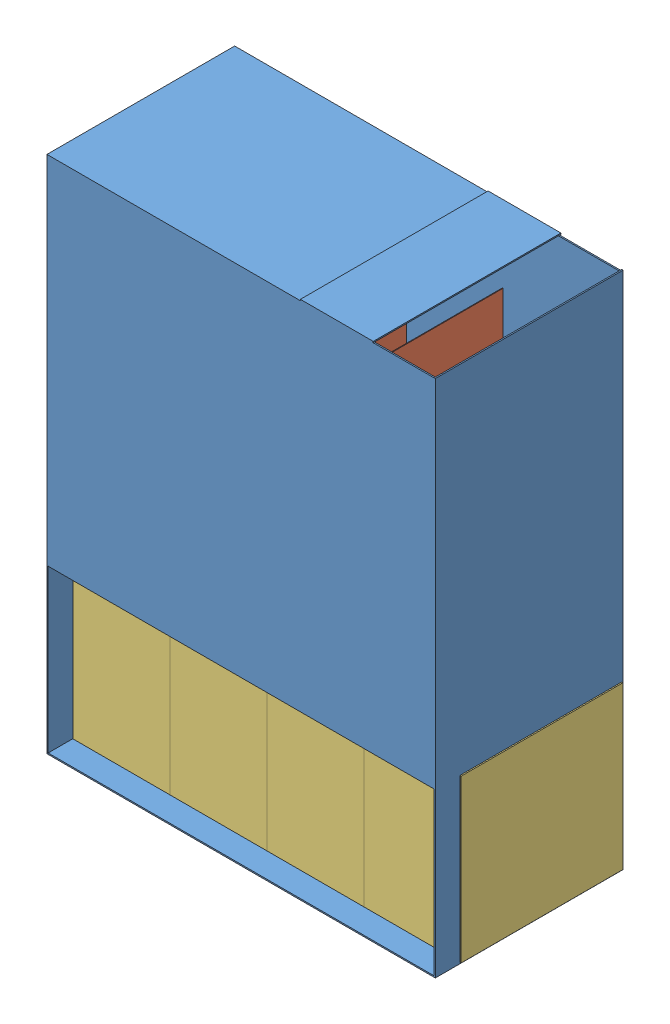
SolidWorks assembly Main body, configuration 默认. Lengths in mm.
Overall size (601.88 803.75 290).
6 component instances, 3 part files, 14 mates.
Components (placement in the parent):
- Shell-1: Shell [默认] at (-498.4129 -376.4154 658.7509) size (600 803.75 290)
- Sorting lane-1: Sorting lane [默认] at (-61.6372 160.9155 679.7509) size (476.17 356.5 269)
- Box-1: Box [默认] at (-346.5374 -374.4154 660.7509) x (0 0 1) z (-1 0 0) size (250 250 150)
- Box-2: Box [默认] at (-346.5374 -374.4154 910.7509) x (0 0 -1) z (1 0 0) size (250 250 150)
- Box-3: Box [默认] at (103.4626 -374.4154 660.7509) x (0 0 1) z (-1 0 0) size (250 250 150)
- Box-4: Box [默认] at (-46.5374 -374.4154 660.7509) x (0 0 1) z (-1 0 0) size (250 250 150)
Mates (geometry in assembly coordinates):
- 重合5: coincident anti-aligned: plane of Shell-1 through (-496.5374 -374.4154 948.7509) normal (0 1 0); plane of Box-1 through (-496.5374 -374.4154 660.7509) normal (0 -1 0)
- 重合6: coincident anti-aligned: plane of Shell-1 through (-496.5374 -374.4154 948.7509) normal (1 0 0); plane of Box-1 through (-496.5374 -374.4154 660.7509) normal (-1 0 0)
- 重合7: coincident anti-aligned: plane of Shell-1 through (-498.4129 423.5846 660.7509) normal (0 0 1); plane of Box-1 through (-496.5374 -374.4154 660.7509) normal (0 0 -1)
- 重合8: coincident anti-aligned: plane of Shell-1 through (-498.4129 423.5846 660.7509) normal (0 0 1); plane of Box-2 through (-196.5374 -374.4154 660.7509) normal (0 0 -1)
- 重合9: coincident anti-aligned: plane of Box-1 through (-346.5374 -374.4154 660.7509) normal (1 0 0); plane of Box-2 through (-346.5374 -374.4154 910.7509) normal (-1 0 0)
- 重合10: coincident anti-aligned: plane of Shell-1 through (-496.5374 -374.4154 948.7509) normal (0 1 0); plane of Box-2 through (-196.5374 -374.4154 910.7509) normal (0 -1 0)
- 重合11: coincident anti-aligned: plane of Box-2 through (-196.5374 -374.4154 910.7509) normal (1 0 0); plane of Box-4 through (-196.5374 -374.4154 660.7509) normal (-1 0 0)
- 重合12: coincident anti-aligned: plane of Shell-1 through (-498.4129 423.5846 660.7509) normal (0 0 1); plane of Box-4 through (-196.5374 -374.4154 660.7509) normal (0 0 -1)
- 重合13: coincident anti-aligned: plane of Shell-1 through (-496.5374 -374.4154 948.7509) normal (0 1 0); plane of Box-4 through (-196.5374 -374.4154 660.7509) normal (0 -1 0)
- 重合14: coincident anti-aligned: plane of Box-3 through (-46.5374 -374.4154 660.7509) normal (-1 0 0); plane of Box-4 through (-46.5374 -374.4154 660.7509) normal (1 0 0)
- 重合15: coincident anti-aligned: plane of Shell-1 through (-498.4129 423.5846 660.7509) normal (0 0 1); plane of Box-3 through (-46.5374 -374.4154 660.7509) normal (0 0 -1)
- 重合17: coincident anti-aligned: plane of Shell-1 through (-496.5374 -374.4154 948.7509) normal (0 1 0); plane of Box-3 through (-46.5374 -374.4154 660.7509) normal (0 -1 0)
- 相切1: tangent: plane of Shell-1 through (99.5871 -374.4154 948.7509) normal (-1 0 0); cylinder of Sorting lane-1 through (85.5871 245.9155 660.7509) axis (0 0 1) radius 14
- 重合18: coincident aligned: plane of Shell-1 through (-498.4129 423.5846 660.7509) normal (0 0 1); circle of Sorting lane-1
